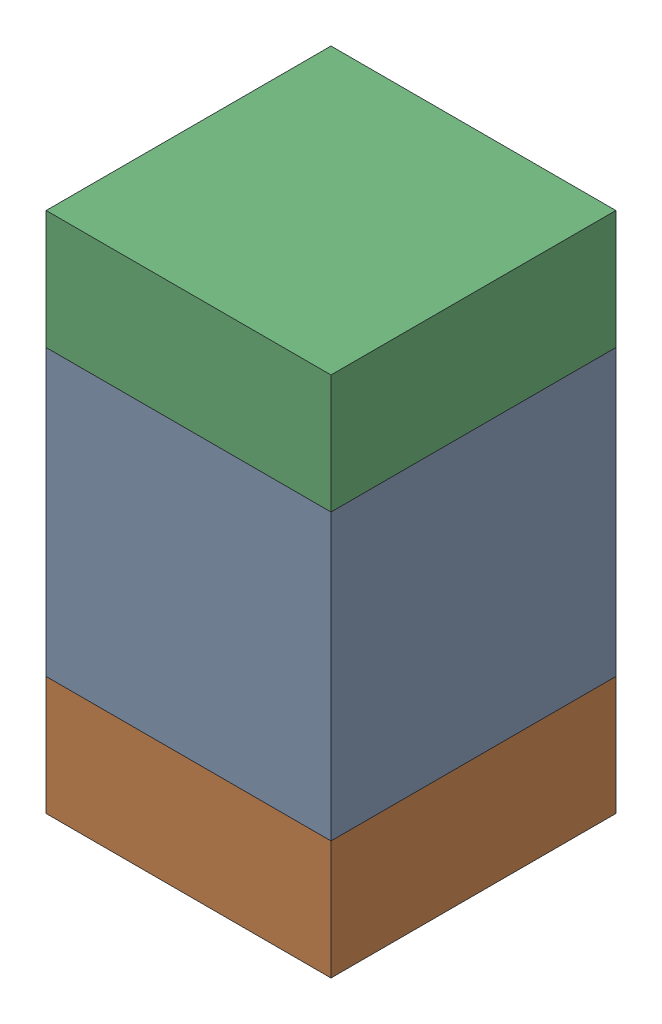
SolidWorks assembly C314_1PCB, configuration Default. Lengths in mm.
Overall size (0.6 1.1 0.6).
6 component instances, 2 part files, 0 mates.
Components (placement in the parent):
- 761606048-1: 761606048 [Default] at (126.5 108.3 -2.2638) size (0.6 0.6 0.6)
  - Extruded_9-1: Extruded_9 [Default] at origin size (0.6 0.6 0.6)
- 854785296-1: 854785296 [Default] at (126.5 107.875 -2.2638) size (0.6 0.25 0.6)
  - Extruded_10-1: Extruded_10 [Default] at origin size (0.6 0.25 0.6)
- 854785296-2: 854785296 [Default] at (126.5 108.725 -2.2638) size (0.6 0.25 0.6)
  - Extruded_10-1: Extruded_10 [Default] at origin size (0.6 0.25 0.6)
